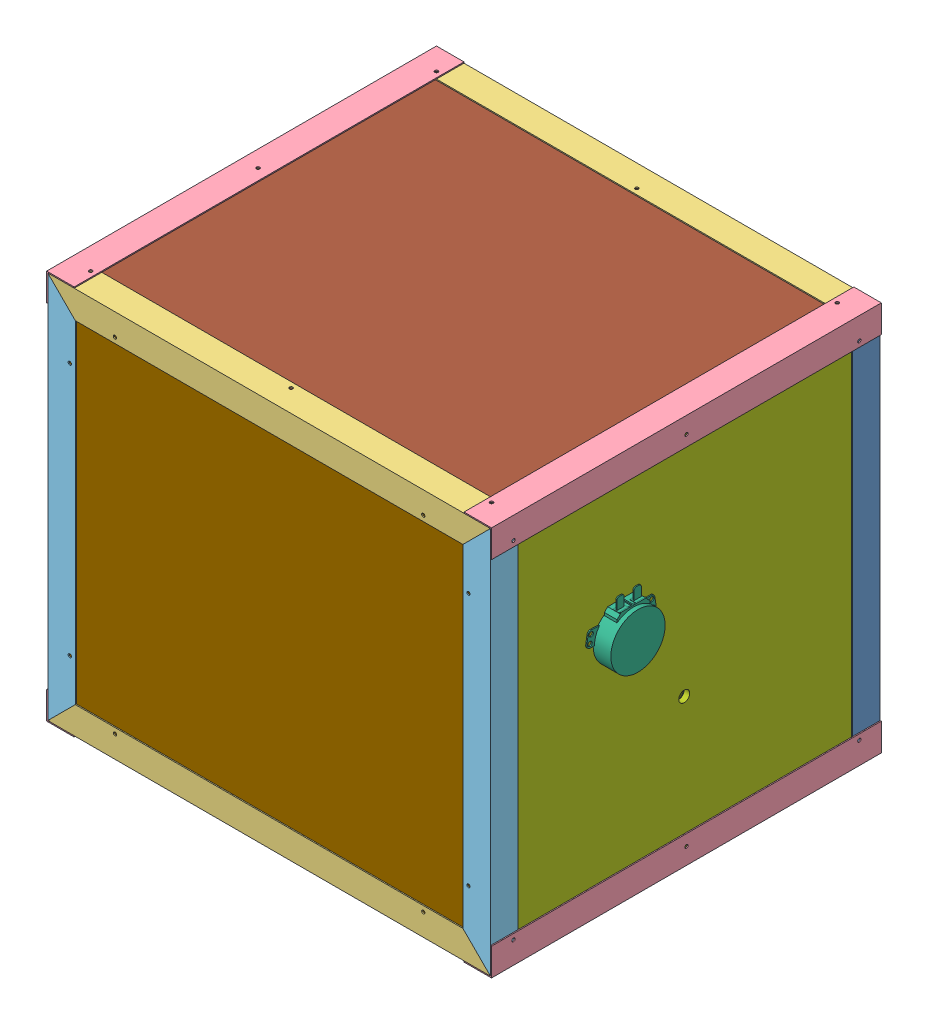
SolidWorks assembly INCUBADORA3.2, configuration Predeterminado. Lengths in mm.
Overall size (420 365.7 354).
45 component instances, 28 part files, 76 mates.
Components (placement in the parent):
- Soporte_Estructura_vertical_frontalIZQ_35x2.5x0.1-1: Soporte_Estructura_vertical_frontalIZQ_35x2.5x0.1 [Predeterminado] at (-68.7256 99.4418 337.5001) size (25 350 25)
- Soporte_Estructura_vertical_frontalDER_35x2.5x0.1-1: Soporte_Estructura_vertical_frontalDER_35x2.5x0.1 [Predeterminado] at (-579.6091 -128.1974 337.5001) x (-1 0 0) z (0 0 1) size (25 350 25)
- Soporte_Estructura_Horizontal_40x2.5x0.1-1: Soporte_Estructura_Horizontal_40x2.5x0.1 [Predeterminado] at (-416.987 216.064 337.5001) x (0 1 0) z (0 0 1) size (25 400 25)
- Soporte_Estructura_Horizontal_40x2.5x0.1-2: Soporte_Estructura_Horizontal_40x2.5x0.1 [Predeterminado] at (-231.3477 -244.8196 337.5001) x (0 -1 0) z (0 0 1) size (25 400 25)
- Soporte_Estructura_Esquinas_35.4x2.5x0.1-1: Soporte_Estructura_Esquinas_35.4x2.5x0.1 [Predeterminado] at (-66.9091 162.6222 626.3194) x (1 0 0) z (0 -1 0) size (25 354 25)
- Soporte_Estructura_Esquinas_35.4x2.5x0.1-2: Soporte_Estructura_Esquinas_35.4x2.5x0.1 [Predeterminado] at (-526.1674 217.8804 626.3194) x (0 1 0) z (1 0 0) size (25 354 25)
- Soporte_Estructura_Esquinas_35.4x2.5x0.1-3: Soporte_Estructura_Esquinas_35.4x2.5x0.1 [Predeterminado] at (-66.9091 -191.3778 402.6808) x (1 0 0) z (0 1 0) size (25 354 25)
- Soporte_Estructura_Esquinas_35.4x2.5x0.1-4: Soporte_Estructura_Esquinas_35.4x2.5x0.1 [Predeterminado] at (-581.4256 -191.3778 626.3194) x (-1 0 0) z (0 1 0) size (25 354 25)
- Soporte_Estructura_vertica_35x2.5x0.1-1: Soporte_Estructura_vertica_35x2.5x0.1 [Predeterminado] at (-579.6091 99.4418 691.5001) x (-1 0 0) z (0 0 -1) size (25 350 25)
- Soporte_Estructura_Horizontal_40x2.5x0.1-3: Soporte_Estructura_Horizontal_40x2.5x0.1 [Predeterminado] at (-231.3477 216.064 691.5001) x (0 1 0) z (0 0 -1) size (25 400 25)
- Soporte_Estructura_vertica_35x2.5x0.1-2: Soporte_Estructura_vertica_35x2.5x0.1 [Predeterminado] at (-68.7256 -128.1974 691.5001) x (1 0 0) z (0 0 -1) size (25 350 25)
- Soporte_Estructura_Horizontal_40x2.5x0.1-4: Soporte_Estructura_Horizontal_40x2.5x0.1 [Predeterminado] at (-416.987 -244.8196 691.5001) x (0 -1 0) z (0 0 -1) size (25 400 25)
- PVC_Derecho_34x34x0.5-1: PVC_Derecho_34x34x0.5 [Predeterminado] at (-524.1674 106.0862 623.4473) x (0 0 -1) z (1 0 0) size (340 340 5)
- PVC_Izquierdo_34x34x0.5-2: PVC_Izquierdo_34x34x0.5 [Predeterminado] at (-129.1674 106.0862 623.4473) x (0 0 -1) z (1 0 0) size (340 340 5)
- PVC_15x39x0.5-1: PVC_15x39x0.5 [Predeterminado] at (-454.5461 96.675 338.5001) x (0 1 0) z (0 0 1) size (120 390 5)
- PVC_FONDO_34x39x0.5-1: PVC_FONDO_34x39x0.5 [Predeterminado] at (-178.7034 94.5694 685.5001) x (0 -1 0) z (0 0 1) size (340 390 5)
- Soporte_Estructura_vertical_central-IZQ_35x2.5x0.1-1: Soporte_Estructura_vertical_central-IZQ_35x2.5x0.1 [Predeterminado] at (-73.8274 99.4418 502.0001) size (25 352 25)
- PVC_34x39x0.5-4: PVC_34x39x0.5 [Predeterminado] at (-178.7034 160.6222 576.1027) x (0 0 -1) z (0 -1 0) size (340 390 5)
- Soporte_Estructura_vertical_central-DER_35x2.5x0.1-2: Soporte_Estructura_vertical_central-DER_35x2.5x0.1 [Predeterminado] at (-574.5074 -128.1974 502.0001) x (-1 0 0) z (0 0 1) size (25 352 25)
- PVC_34x39x0.5-5: PVC_34x39x0.5 [Predeterminado] at (-469.6313 -189.3778 576.1027) x (0 0 -1) z (0 1 0) size (340 390 5)
- Powder Coating Oven Light Unit-1: Powder Coating Oven Light Unit [Default] at (-262.6293 98.7262 682.5791) x (-0.906504 -0.422198 0) z (0.422198 -0.906504 0) size (113.79 123.2 113.79)
  - Porcelain Lampholder Light Fixture-1: Porcelain Lampholder Light Fixture [Default] at origin size (113.79 41.16 113.79)
  - Light Bulb-1: Light Bulb [Default] at (0 12.954 0) x (0.978795 0 0.204841) z (-0.204841 0 0.978795) size (60.2 107.19 60.2)
- Bandeja_Huevos_27x36x2.5-1: Bandeja_Huevos_27x36x2.5 [Predeterminado] at (-320.2845 -450.5799 652.869) x (0 -0.573576 -0.819152) z (0 0.819152 -0.573576) size (272 362 42)
  - Soporte_Bandeja_Horizonta_40x2.5x0.1-1: Soporte_Bandeja_Horizonta_40x2.5x0.1 [Predeterminado] at (53.9361 154.3977 387.5) size (25 360 25)
  - Soporte_Bandeja_Horizonta_40x2.5x0.1-4: Soporte_Bandeja_Horizonta_40x2.5x0.1 [Predeterminado] at (-274.8673 -152.6319 387.5) x (-1 0 0) z (0 0 1) size (25 360 25)
  - Soporte_Bandeja_Vertical_27x2.5x0.1-2: Soporte_Bandeja_Vertical_27x2.5x0.1 [Predeterminado] at (-218.9804 210.2846 386.5) x (0 1 0) z (0 0 1) size (25 270 25)
  - Soporte_Bandeja_Vertical_27x2.5x0.1-3: Soporte_Bandeja_Vertical_27x2.5x0.1 [Predeterminado] at (-1.9508 -208.5189 386.5) x (0 -1 0) z (0 0 1) size (25 270 25)
  - Bandeja_Down_27x36x0.5-1: Bandeja_Down_27x36x0.5 [Predeterminado] at (-199.9841 -101.0844 388.5) x (0 1 0) z (0 0 1) size (350 260 3)
  - Bandeja_Up_27x36x0.3-1: Bandeja_Up_27x36x0.3 [Predeterminado] at (-21.9173 102.8502 423.5) x (0 -1 0) z (0 0 1) size (360 270.04 3)
  - Bandeja_Huevo_levantador-1: Bandeja_Huevo_levantador [Predeterminado] at (-245.4656 -92.1249 405.9419) x (0 1 0) z (1 0 0) size (20 40 2)
  - Bandeja_Huevo_levantador-2: Bandeja_Huevo_levantador [Predeterminado] at (24.5344 -158.1093 405.9419) x (0 -1 0) z (-1 0 0) size (20 40 2)
  - Bandeja_Huevo_levantador-3: Bandeja_Huevo_levantador [Predeterminado] at (24.5344 93.8907 405.9419) x (0 -1 0) z (-1 0 0) size (20 40 2)
  - Bandeja_Huevo_levantador-4: Bandeja_Huevo_levantador [Predeterminado] at (-243.4656 135.8907 405.9419) x (0 -1 0) z (-1 0 0) size (20 40 2)
- fan-1: fan [Default] at (-269.7526 115.6222 502.0001) x (1 0 0) z (0 -1 0) size (80 25.5 80)
  - stator-1: stator [Default] at origin size (80 25.5 80)
  - rotor-1: rotor [Default] at (0 2.5 0) x (0.997026 0 -0.077067) z (0.077067 0 0.997026) size (70 23.35 70)
- 20X4LCD JHD204A-1: 20X4LCD JHD204A [Default] at (-419.5674 97.6222 346.8001) x (1 0 0) z (0 1 0) size (98.3 9.76 60)
- Puerta_Incubadora3-1: Puerta_Incubadora3 [Predeterminado] at (33.2793 -210.2279 335.9779) x (-1 0 0) z (0 0 -1) size (380 220 5) (hidden)
- Soporte ventilador y circuitos-1: Soporte ventilador y circuitos [Predeterminado] at (-146.9783 146.8452 502.0001) x (-1 0 0) z (0 0 -1) size (390 95 5)
- User Library-Motor do prato 4W 6RPM 120V Cód_-2: User Library-Motor do prato 4W 6RPM 120V Cód_ [Padrão] at (-106.1674 23.2722 574.5001) x (0 0 -1) z (0 1 0) size (63.04 27.4 60.05)
- Fuente de poder-1: Fuente de poder [По умолчанию] at (-478.4174 150.0993 636.2001) x (0 0 1) z (1 0 0) size (99.45 35.23 81.3)
  - БП MW RD-35-R8-1: БП MW RD-35-R8 [По умолчанию] at origin size (97.91 28.9 79.31)
  - Основание БП-1: Основание БП [По умолчанию] at (0 -4.5229 -0.25) size (98.6 35.1 81)
  - Крышка БП-1: Крышка БП [По умолчанию] at (-6.45 29.7 0.55) x (-1 0 0) z (0 0 -1) size (98.4 35 80)
Mates (geometry in assembly coordinates):
- Coincidente1: coincident anti-aligned: plane of Soporte_Estructura_vertical_frontalIZQ_35x2.5x0.1-1 through (-124.1674 160.6222 338.5001) normal (-0.707107 0.707107 0); plane of Soporte_Estructura_Horizontal_40x2.5x0.1-1 through (-124.1674 160.6222 338.5001) normal (0.707107 -0.707107 0)
- Coincidente2: coincident aligned: plane of Soporte_Estructura_vertical_frontalIZQ_35x2.5x0.1-1 through (-68.7256 99.4418 337.5001) normal (0 0 -1); plane of Soporte_Estructura_Horizontal_40x2.5x0.1-1 through (-416.987 216.064 337.5001) normal (0 0 -1)
- Coincidente3: coincident aligned: line of Soporte_Estructura_vertical_frontalIZQ_35x2.5x0.1-1 through (-124.1674 160.6222 362.5001) axis (0 0 -1); line of Soporte_Estructura_Horizontal_40x2.5x0.1-1 through (-124.1674 160.6222 362.5001) axis (0 0 -1)
- Coincidente4: coincident anti-aligned: plane of Soporte_Estructura_vertical_frontalDER_35x2.5x0.1-1 through (-524.1674 160.6222 338.5001) normal (0.707107 0.707107 0); plane of Soporte_Estructura_Horizontal_40x2.5x0.1-1 through (-524.1674 160.6222 338.5001) normal (-0.707107 -0.707107 0)
- Coincidente5: coincident aligned: plane of Soporte_Estructura_vertical_frontalDER_35x2.5x0.1-1 through (-579.6091 -128.1974 337.5001) normal (0 0 -1); plane of Soporte_Estructura_Horizontal_40x2.5x0.1-1 through (-416.987 216.064 337.5001) normal (0 0 -1)
- Coincidente6: coincident aligned: line of Soporte_Estructura_vertical_frontalDER_35x2.5x0.1-1 through (-524.1674 160.6222 362.5001) axis (0 0 -1); line of Soporte_Estructura_Horizontal_40x2.5x0.1-1 through (-524.1674 160.6222 362.5001) axis (0 0 -1)
- Coincidente7: coincident anti-aligned: plane of Soporte_Estructura_vertical_frontalDER_35x2.5x0.1-1 through (-524.1674 -189.3778 338.5001) normal (0.707107 -0.707107 0); plane of Soporte_Estructura_Horizontal_40x2.5x0.1-2 through (-524.1674 -189.3778 338.5001) normal (-0.707107 0.707107 0)
- Coincidente8: coincident aligned: plane of Soporte_Estructura_vertical_frontalDER_35x2.5x0.1-1 through (-579.6091 -128.1974 337.5001) normal (0 0 -1); plane of Soporte_Estructura_Horizontal_40x2.5x0.1-2 through (-231.3477 -244.8196 337.5001) normal (0 0 -1)
- Coincidente9: coincident aligned: line of Soporte_Estructura_vertical_frontalDER_35x2.5x0.1-1 through (-524.1674 -189.3778 362.5001) axis (0 0 -1); line of Soporte_Estructura_Horizontal_40x2.5x0.1-2 through (-524.1674 -189.3778 362.5001) axis (0 0 -1)
- Coincidente10: coincident anti-aligned: plane of Soporte_Estructura_Horizontal_40x2.5x0.1-1 through (-524.1674 161.6222 362.5001) normal (0 1 0); plane of Soporte_Estructura_Esquinas_35.4x2.5x0.1-1 through (-66.9091 161.6222 626.3194) normal (0 -1 0)
- Coincidente11: coincident anti-aligned: plane of Soporte_Estructura_vertical_frontalIZQ_35x2.5x0.1-1 through (-123.1674 160.6222 362.5001) normal (1 0 0); plane of Soporte_Estructura_Esquinas_35.4x2.5x0.1-1 through (-123.1674 137.6222 691.5001) normal (-1 0 0)
- Coincidente12: coincident aligned: plane of Soporte_Estructura_vertical_frontalIZQ_35x2.5x0.1-1 through (-68.7256 99.4418 337.5001) normal (0 0 -1); plane of Soporte_Estructura_Esquinas_35.4x2.5x0.1-1 through (-123.1674 137.6222 337.5001) normal (0 0 -1)
- Coincidente13: coincident anti-aligned: plane of Soporte_Estructura_Horizontal_40x2.5x0.1-1 through (-524.1674 161.6222 362.5001) normal (0 1 0); plane of Soporte_Estructura_Esquinas_35.4x2.5x0.1-2 through (-501.1674 161.6222 691.5001) normal (0 -1 0)
- Coincidente14: coincident anti-aligned: plane of Soporte_Estructura_vertical_frontalDER_35x2.5x0.1-1 through (-525.1674 -189.3778 362.5001) normal (-1 0 0); plane of Soporte_Estructura_Esquinas_35.4x2.5x0.1-2 through (-525.1674 217.8804 626.3194) normal (1 0 0)
- Coincidente16: coincident aligned: plane of Soporte_Estructura_Horizontal_40x2.5x0.1-1 through (-416.987 216.064 337.5001) normal (0 0 -1); plane of Soporte_Estructura_Esquinas_35.4x2.5x0.1-2 through (-501.1674 161.6222 337.5001) normal (0 0 -1)
- Coincidente17: coincident anti-aligned: plane of Soporte_Estructura_Horizontal_40x2.5x0.1-2 through (-124.1674 -190.3778 362.5001) normal (0 -1 0); plane of Soporte_Estructura_Esquinas_35.4x2.5x0.1-3 through (-66.9091 -190.3778 402.6808) normal (0 1 0)
- Coincidente19: coincident anti-aligned: plane of Soporte_Estructura_vertical_frontalIZQ_35x2.5x0.1-1 through (-123.1674 160.6222 362.5001) normal (1 0 0); plane of Soporte_Estructura_Esquinas_35.4x2.5x0.1-3 through (-123.1674 -166.3778 337.5001) normal (-1 0 0)
- Coincidente20: coincident aligned: plane of Soporte_Estructura_vertical_frontalIZQ_35x2.5x0.1-1 through (-68.7256 99.4418 337.5001) normal (0 0 -1); plane of Soporte_Estructura_Esquinas_35.4x2.5x0.1-3 through (-123.1674 -166.3778 337.5001) normal (0 0 -1)
- Coincidente21: coincident anti-aligned: plane of Soporte_Estructura_Horizontal_40x2.5x0.1-2 through (-124.1674 -190.3778 362.5001) normal (0 -1 0); plane of Soporte_Estructura_Esquinas_35.4x2.5x0.1-4 through (-581.4256 -190.3778 626.3194) normal (0 1 0)
- Coincidente22: coincident anti-aligned: plane of Soporte_Estructura_vertical_frontalDER_35x2.5x0.1-1 through (-525.1674 -189.3778 362.5001) normal (-1 0 0); plane of Soporte_Estructura_Esquinas_35.4x2.5x0.1-4 through (-525.1674 -166.3778 691.5001) normal (1 0 0)
- Coincidente23: coincident aligned: plane of Soporte_Estructura_vertical_frontalDER_35x2.5x0.1-1 through (-579.6091 -128.1974 337.5001) normal (0 0 -1); plane of Soporte_Estructura_Esquinas_35.4x2.5x0.1-4 through (-525.1674 -166.3778 337.5001) normal (0 0 -1)
- Coincidente24: coincident anti-aligned: plane of Soporte_Estructura_Esquinas_35.4x2.5x0.1-2 through (-525.1674 217.8804 626.3194) normal (1 0 0); plane of Soporte_Estructura_vertica_35x2.5x0.1-1 through (-525.1674 160.6222 666.5001) normal (-1 0 0)
- Coincidente25: coincident aligned: plane of Soporte_Estructura_Esquinas_35.4x2.5x0.1-2 through (-501.1674 161.6222 691.5001) normal (0 0 1); plane of Soporte_Estructura_vertica_35x2.5x0.1-1 through (-579.6091 99.4418 691.5001) normal (0 0 1)
- Coincidente27: coincident anti-aligned: plane of Soporte_Estructura_Esquinas_35.4x2.5x0.1-2 through (-501.1674 161.6222 691.5001) normal (0 -1 0); plane of Soporte_Estructura_Horizontal_40x2.5x0.1-3 through (-124.1674 161.6222 666.5001) normal (0 1 0)
- Coincidente28: coincident aligned: plane of Soporte_Estructura_vertica_35x2.5x0.1-1 through (-579.6091 99.4418 691.5001) normal (0 0 1); plane of Soporte_Estructura_Horizontal_40x2.5x0.1-3 through (-231.3477 216.064 691.5001) normal (0 0 1)
- Coincidente29: coincident anti-aligned: plane of Soporte_Estructura_vertica_35x2.5x0.1-1 through (-524.1674 160.6222 690.5001) normal (0.707107 0.707107 0); plane of Soporte_Estructura_Horizontal_40x2.5x0.1-3 through (-524.1674 160.6222 690.5001) normal (-0.707107 -0.707107 0)
- Coincidente30: coincident aligned: plane of Soporte_Estructura_Horizontal_40x2.5x0.1-3 through (-231.3477 216.064 691.5001) normal (0 0 1); plane of Soporte_Estructura_vertica_35x2.5x0.1-2 through (-68.7256 -128.1974 691.5001) normal (0 0 1)
- Coincidente31: coincident anti-aligned: plane of Soporte_Estructura_Esquinas_35.4x2.5x0.1-1 through (-123.1674 137.6222 691.5001) normal (-1 0 0); plane of Soporte_Estructura_vertica_35x2.5x0.1-2 through (-123.1674 -189.3778 666.5001) normal (1 0 0)
- Coincidente32: coincident anti-aligned: plane of Soporte_Estructura_Horizontal_40x2.5x0.1-3 through (-124.1674 160.6222 690.5001) normal (0.707107 -0.707107 0); plane of Soporte_Estructura_vertica_35x2.5x0.1-2 through (-124.1674 160.6222 690.5001) normal (-0.707107 0.707107 0)
- Coincidente33: coincident aligned: plane of Soporte_Estructura_vertica_35x2.5x0.1-2 through (-68.7256 -128.1974 691.5001) normal (0 0 1); plane of Soporte_Estructura_Horizontal_40x2.5x0.1-4 through (-416.987 -244.8196 691.5001) normal (0 0 1)
- Coincidente34: coincident anti-aligned: plane of Soporte_Estructura_Esquinas_35.4x2.5x0.1-4 through (-581.4256 -190.3778 626.3194) normal (0 1 0); plane of Soporte_Estructura_Horizontal_40x2.5x0.1-4 through (-524.1674 -190.3778 666.5001) normal (0 -1 0)
- Coincidente35: coincident anti-aligned: plane of Soporte_Estructura_vertica_35x2.5x0.1-2 through (-124.1674 -189.3778 690.5001) normal (-0.707107 -0.707107 0); plane of Soporte_Estructura_Horizontal_40x2.5x0.1-4 through (-124.1674 -189.3778 690.5001) normal (0.707107 0.707107 0)
- Coincidente36: coincident: moEndPointRef_w of Soporte_Estructura_vertica_35x2.5x0.1-2; moEndPointRef_w of Soporte_Estructura_Horizontal_40x2.5x0.1-4
- Coincidente40: coincident anti-aligned: plane of Soporte_Estructura_vertica_35x2.5x0.1-1 through (-524.1674 160.6222 666.5001) normal (1 0 0); plane of PVC_Derecho_34x34x0.5-1 through (-524.1674 106.0862 623.4473) normal (-1 0 0)
- Distancia3: distance = 6 mm anti-aligned: plane of PVC_Derecho_34x34x0.5-1 through (-519.1674 155.6222 344.5001) normal (0 0 -1); plane of Soporte_Estructura_vertical_frontalDER_35x2.5x0.1-1 through (-579.6091 -128.1974 338.5001) normal (0 0 1)
- Distancia4: distance = 5 mm anti-aligned: plane of Soporte_Estructura_Horizontal_40x2.5x0.1-1 through (-524.1674 160.6222 362.5001) normal (0 -1 0); plane of PVC_Derecho_34x34x0.5-1 through (-519.1674 155.6222 684.5001) normal (0 1 0)
- Coincidente48: coincident anti-aligned: plane of Soporte_Estructura_vertica_35x2.5x0.1-2 through (-124.1674 -189.3778 666.5001) normal (-1 0 0); plane of PVC_Izquierdo_34x34x0.5-2 through (-124.1674 106.0862 623.4473) normal (1 0 0)
- Distancia8: distance = 6 mm anti-aligned: plane of Soporte_Estructura_vertica_35x2.5x0.1-2 through (-68.7256 -128.1974 690.5001) normal (0 0 -1); plane of PVC_Izquierdo_34x34x0.5-2 through (-124.1674 155.6222 684.5001) normal (0 0 1)
- Distancia9: distance = 6 mm anti-aligned: plane of PVC_Izquierdo_34x34x0.5-2 through (-124.1674 -184.3778 684.5001) normal (0 -1 0); plane of Soporte_Estructura_Esquinas_35.4x2.5x0.1-3 through (-66.9091 -190.3778 402.6808) normal (0 1 0)
- Distancia11: distance = 5 mm anti-aligned: plane of Soporte_Estructura_vertical_frontalDER_35x2.5x0.1-1 through (-524.1674 -189.3778 362.5001) normal (1 0 0); plane of PVC_15x39x0.5-1 through (-519.1674 35.6222 343.5001) normal (-1 0 0)
- Distancia10: distance = 5 mm anti-aligned: plane of PVC_15x39x0.5-1 through (-519.1674 155.6222 343.5001) normal (0 1 0); plane of Soporte_Estructura_Horizontal_40x2.5x0.1-1 through (-524.1674 160.6222 362.5001) normal (0 -1 0)
- Coincidente53: coincident anti-aligned: plane of Soporte_Estructura_vertical_frontalDER_35x2.5x0.1-1 through (-579.6091 -128.1974 338.5001) normal (0 0 1); plane of PVC_15x39x0.5-1 through (-454.5461 96.675 338.5001) normal (0 0 -1)
- Coincidente54: coincident anti-aligned: plane of Soporte_Estructura_vertica_35x2.5x0.1-2 through (-68.7256 -128.1974 690.5001) normal (0 0 -1); plane of PVC_FONDO_34x39x0.5-1 through (-178.7034 94.5694 690.5001) normal (0 0 1)
- Distancia12: distance = 5 mm anti-aligned: plane of PVC_FONDO_34x39x0.5-1 through (-129.1674 155.6222 690.5001) normal (1 0 0); plane of Soporte_Estructura_vertica_35x2.5x0.1-2 through (-124.1674 -189.3778 666.5001) normal (-1 0 0)
- Distancia13: distance = 5 mm anti-aligned: plane of Soporte_Estructura_Horizontal_40x2.5x0.1-3 through (-124.1674 160.6222 666.5001) normal (0 -1 0); plane of PVC_FONDO_34x39x0.5-1 through (-129.1674 155.6222 690.5001) normal (0 1 0)
- Coincidente57: coincident anti-aligned: plane of PVC_Izquierdo_34x34x0.5-2 through (-129.1674 106.0862 623.4473) normal (-1 0 0); plane of Soporte_Estructura_vertical_central-IZQ_35x2.5x0.1-1 through (-129.1674 161.6222 527.0001) normal (1 0 0)
- Coincidente58: coincident anti-aligned: plane of Soporte_Estructura_Esquinas_35.4x2.5x0.1-3 through (-66.9091 -190.3778 402.6808) normal (0 1 0); plane of Soporte_Estructura_vertical_central-IZQ_35x2.5x0.1-1 through (-130.1674 -190.3778 527.0001) normal (0 -1 0)
- Coincidente59: coincident anti-aligned: plane of Soporte_Estructura_Horizontal_40x2.5x0.1-1 through (-524.1674 160.6222 362.5001) normal (0 -1 0); plane of PVC_34x39x0.5-4 through (-178.7034 160.6222 576.1027) normal (0 1 0)
- Distancia15: distance = 5 mm anti-aligned: plane of Soporte_Estructura_vertical_frontalDER_35x2.5x0.1-1 through (-524.1674 -189.3778 362.5001) normal (1 0 0); plane of PVC_34x39x0.5-4 through (-519.1674 155.6222 499.5001) normal (-1 0 0)
- Distancia16: distance = 6 mm anti-aligned: plane of Soporte_Estructura_Horizontal_40x2.5x0.1-1 through (-416.987 216.064 338.5001) normal (0 0 1); plane of PVC_34x39x0.5-4 through (-129.1674 155.6222 344.5001) normal (0 0 -1)
- Coincidente63: coincident anti-aligned: plane of PVC_Derecho_34x34x0.5-1 through (-519.1674 106.0862 623.4473) normal (1 0 0); plane of Soporte_Estructura_vertical_central-DER_35x2.5x0.1-2 through (-519.1674 -190.3778 527.0001) normal (-1 0 0)
- Coincidente64: coincident anti-aligned: plane of Soporte_Estructura_Esquinas_35.4x2.5x0.1-2 through (-501.1674 161.6222 691.5001) normal (0 -1 0); plane of Soporte_Estructura_vertical_central-DER_35x2.5x0.1-2 through (-518.1674 161.6222 527.0001) normal (0 1 0)
- Coincidente65: coincident anti-aligned: plane of Soporte_Estructura_Horizontal_40x2.5x0.1-4 through (-524.1674 -189.3778 666.5001) normal (0 1 0); plane of PVC_34x39x0.5-5 through (-469.6313 -189.3778 576.1027) normal (0 -1 0)
- Distancia17: distance = 5 mm anti-aligned: plane of Soporte_Estructura_vertica_35x2.5x0.1-2 through (-124.1674 -189.3778 666.5001) normal (-1 0 0); plane of PVC_34x39x0.5-5 through (-129.1674 -184.3778 684.5001) normal (1 0 0)
- Distancia18: distance = 6 mm anti-aligned: plane of PVC_34x39x0.5-5 through (-519.1674 -184.3778 344.5001) normal (0 0 -1); plane of Soporte_Estructura_Horizontal_40x2.5x0.1-2 through (-231.3477 -244.8196 338.5001) normal (0 0 1)
- Concéntrica2: concentric aligned: cylinder of Soporte_Estructura_vertical_central-DER_35x2.5x0.1-2 through (-518.1674 -60.3778 514.5001) axis (-1 0 0) radius 5; cylinder of Bandeja_Huevos_27x36x2.5-1/Soporte_Bandeja_Vertical_27x2.5x0.1-2 through (-501.1674 -60.3778 514.5001) axis (-1 0 0) radius 5
- Distancia20: distance = 163.5 mm anti-aligned: plane of Soporte_Estructura_vertical_central-IZQ_35x2.5x0.1-1 through (-73.8274 99.4418 502.0001) normal (0 0 -1); plane of Soporte_Estructura_vertical_frontalIZQ_35x2.5x0.1-1 through (-68.7256 99.4418 338.5001) normal (0 0 1)
- Distancia21: distance = 163.5 mm anti-aligned: plane of Soporte_Estructura_vertical_frontalDER_35x2.5x0.1-1 through (-579.6091 -128.1974 338.5001) normal (0 0 1); plane of Soporte_Estructura_vertical_central-DER_35x2.5x0.1-2 through (-574.5074 -128.1974 502.0001) normal (0 0 -1)
- Ángulo límite1: limit planar angle = 3.752458 rad aligned: line of Bandeja_Huevos_27x36x2.5-1/Soporte_Bandeja_Vertical_27x2.5x0.1-3 through (-140.1674 6.8156 632.2553) axis (0 -0.573576 -0.819152); line of Soporte_Estructura_Esquinas_35.4x2.5x0.1-3 through (-123.1674 -166.3778 337.5001) axis (0 0 1)
- Distancia22: distance = 10 mm anti-aligned: plane of Bandeja_Huevos_27x36x2.5-1/Soporte_Bandeja_Vertical_27x2.5x0.1-3 through (-140.1674 -127.5712 396.7449) normal (1 0 0); plane of Soporte_Estructura_vertical_central-IZQ_35x2.5x0.1-1 through (-130.1674 161.6222 527.0001) normal (-1 0 0)
- Coincidente66: coincident anti-aligned: plane of PVC_FONDO_34x39x0.5-1 through (-178.7034 94.5694 685.5001) normal (0 0 -1); plane of Powder Coating Oven Light Unit-1/Porcelain Lampholder Light Fixture-1 through (-279.2241 105.5714 685.5001) normal (0 0 1)
- Tangente1: tangent anti-aligned: plane of PVC_34x39x0.5-4 through (-178.7034 155.6222 576.1027) normal (0 -1 0); cylinder of Powder Coating Oven Light Unit-1/Porcelain Lampholder Light Fixture-1 through (-262.6293 98.7262 682.5791) axis (0 0 1) radius 56.896
- Coincidente67: coincident anti-aligned: plane of PVC_34x39x0.5-4 through (-178.7034 155.6222 576.1027) normal (0 -1 0); plane of fan-1/stator-1 through (-309.7526 155.6222 527.5001) normal (0 1 0)
- Coincidente68: coincident aligned: plane of PVC_15x39x0.5-1 through (-454.5461 96.675 338.5001) normal (0 0 -1); plane of 20X4LCD JHD204A-1 through (-509.2858 97.6222 338.5001) normal (0 0 -1)
- Distancia23: distance = 2.5 mm anti-aligned: plane of PVC_15x39x0.5-1 through (-369.1674 75.6222 343.5001) normal (0 1 0); plane of 20X4LCD JHD204A-1 through (-509.2858 78.1222 338.5001) normal (0 -1 0)
- Distancia24: distance = 2.5 mm anti-aligned: plane of PVC_15x39x0.5-1 through (-369.1674 75.6222 343.5001) normal (-1 0 0); plane of 20X4LCD JHD204A-1 through (-371.6674 97.6222 338.5001) normal (1 0 0)
- Coincidente69: coincident anti-aligned: plane of Soporte_Estructura_vertical_central-DER_35x2.5x0.1-2 through (-574.5074 -128.1974 502.0001) normal (0 0 -1); plane of Soporte ventilador y circuitos-1 through (-146.9783 146.8452 502.0001) normal (0 0 1)
- Coincidente70: coincident anti-aligned: plane of PVC_34x39x0.5-4 through (-178.7034 155.6222 576.1027) normal (0 -1 0); plane of Soporte ventilador y circuitos-1 through (-129.1674 155.6222 497.0001) normal (0 1 0)
- Coincidente71: coincident anti-aligned: plane of PVC_Izquierdo_34x34x0.5-2 through (-129.1674 106.0862 623.4473) normal (-1 0 0); plane of Soporte ventilador y circuitos-1 through (-129.1674 155.6222 497.0001) normal (1 0 0)
- Coincidente72: coincident anti-aligned: plane of fan-1/stator-1 through (-309.7526 75.6222 502.0001) normal (0 0 -1); plane of Soporte ventilador y circuitos-1 through (-146.9783 146.8452 502.0001) normal (0 0 1)
- Concéntrica4: concentric anti-aligned: cylinder of PVC_Izquierdo_34x34x0.5-2 through (-124.1674 10.6222 574.5001) axis (-1 0 0) radius 3.5; cylinder of User Library-Motor do prato 4W 6RPM 120V Cód_-2 through (-133.5674 10.6222 574.5001) axis (1 0 0) radius 3.5
- Coincidente75: coincident anti-aligned: plane of PVC_Izquierdo_34x34x0.5-2 through (-124.1674 106.0862 623.4473) normal (1 0 0); plane of User Library-Motor do prato 4W 6RPM 120V Cód_-2 through (-124.1674 10.6222 574.5001) normal (-1 0 0)
- Paralelo2: parallel anti-aligned: plane of User Library-Motor do prato 4W 6RPM 120V Cód_-2 through (-114.1674 58.6722 585.5001) normal (0 1 0); plane of Soporte_Estructura_Esquinas_35.4x2.5x0.1-1 through (-66.9091 137.6222 626.3194) normal (0 -1 0)
- Coincidente76: coincident anti-aligned: plane of PVC_Derecho_34x34x0.5-1 through (-519.1674 106.0862 623.4473) normal (1 0 0); plane of Fuente de poder-1/Основание БП-1 through (-519.1674 154.6222 636.2001) normal (-1 0 0)
- Coincidente77: coincident anti-aligned: plane of PVC_34x39x0.5-4 through (-178.7034 155.6222 576.1027) normal (0 -1 0); plane of Fuente de poder-1/Основание БП-1 through (-478.6674 155.6222 636.2001) normal (0 1 0)
- Coincidente78: coincident anti-aligned: plane of PVC_FONDO_34x39x0.5-1 through (-178.7034 94.5694 685.5001) normal (0 0 -1); plane of Fuente de poder-1/Основание БП-1 through (-519.1674 154.6222 685.5001) normal (0 0 1)
